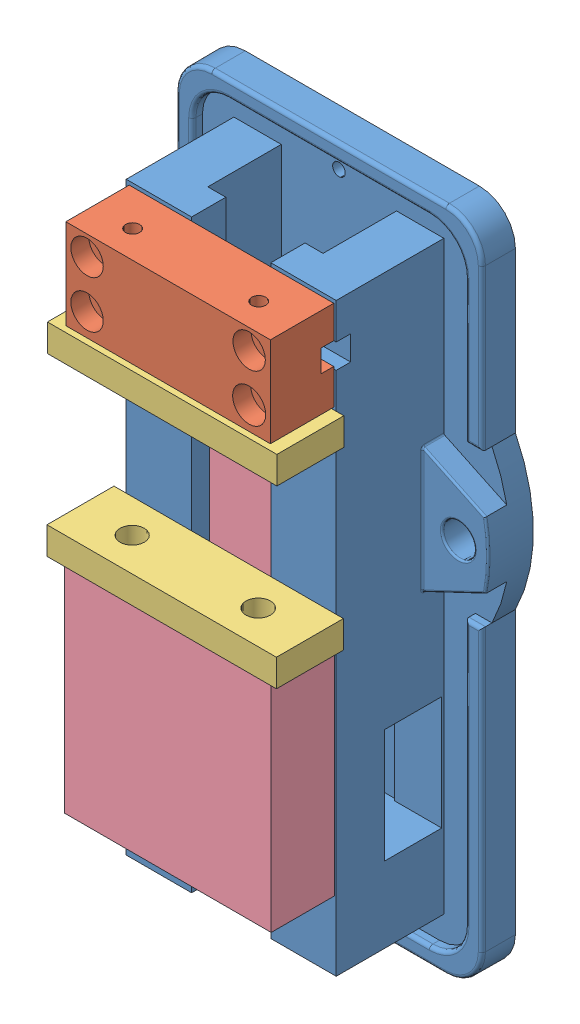
SolidWorks assembly 3in Vice Assembly, configuration Default. Lengths in mm.
Overall size (120.65 234.95 70.74).
5 component instances, 4 part files, 8 mates.
Components (placement in the parent):
- Vice-base-1: Vice-base [Default] at origin size (120.65 234.95 46.23)
- End Block-1: End Block [Default] at (0.0986 86.36 46.228) size (72.14 31.75 22.35)
- jaws-1: jaws [Default] at (0.0986 70.485 58.8645) x (1 0 0) z (0 -1 0) size (80.9 23.62 9.65)
- moving block-1: moving block [Default] at (0 -78.5853 68.58) x (-1 0 0) z (0 0 -1) size (72.9 118.11 56.01)
- jaws-3: jaws [Default] at (0 8.5367 58.928) x (1 0 0) z (0 -1 0) size (80.9 23.62 9.65)
Mates (geometry in assembly coordinates):
- Coincident1: coincident anti-aligned: plane of Vice-base-1 through (0 0 46.228) normal (0 0 1); plane of End Block-1 through (0.0986 86.36 46.228) normal (0 0 -1)
- Coincident2: coincident aligned: line of Vice-base-1 through (-13.97 90.805 46.228) axis (-1 0 0); line of End Block-1 through (36.1666 90.805 46.228) axis (-1 0 0)
- Coincident4: coincident anti-aligned: plane of End Block-1 through (-35.9694 70.485 68.58) normal (0 -1 0); plane of jaws-1 through (0.0986 70.485 58.8645) normal (0 1 0)
- Concentric1: concentric aligned: circle of End Block-1; circle of jaws-1
- Coincident5: coincident anti-aligned: plane of Vice-base-1 through (0 0 46.228) normal (0 0 1); plane of moving block-1 through (-36.449 -1.1153 46.228) normal (0 0 -1)
- Coincident6: coincident anti-aligned: plane of moving block-1 through (0 -1.1153 30.8317) normal (0 1 0); plane of jaws-3 through (0 -1.1153 58.928) normal (0 -1 0)
- Concentric2: concentric anti-aligned: circle of moving block-1; circle of jaws-3
- Concentric3: concentric anti-aligned: circle of Vice-base-1; circle of moving block-1
